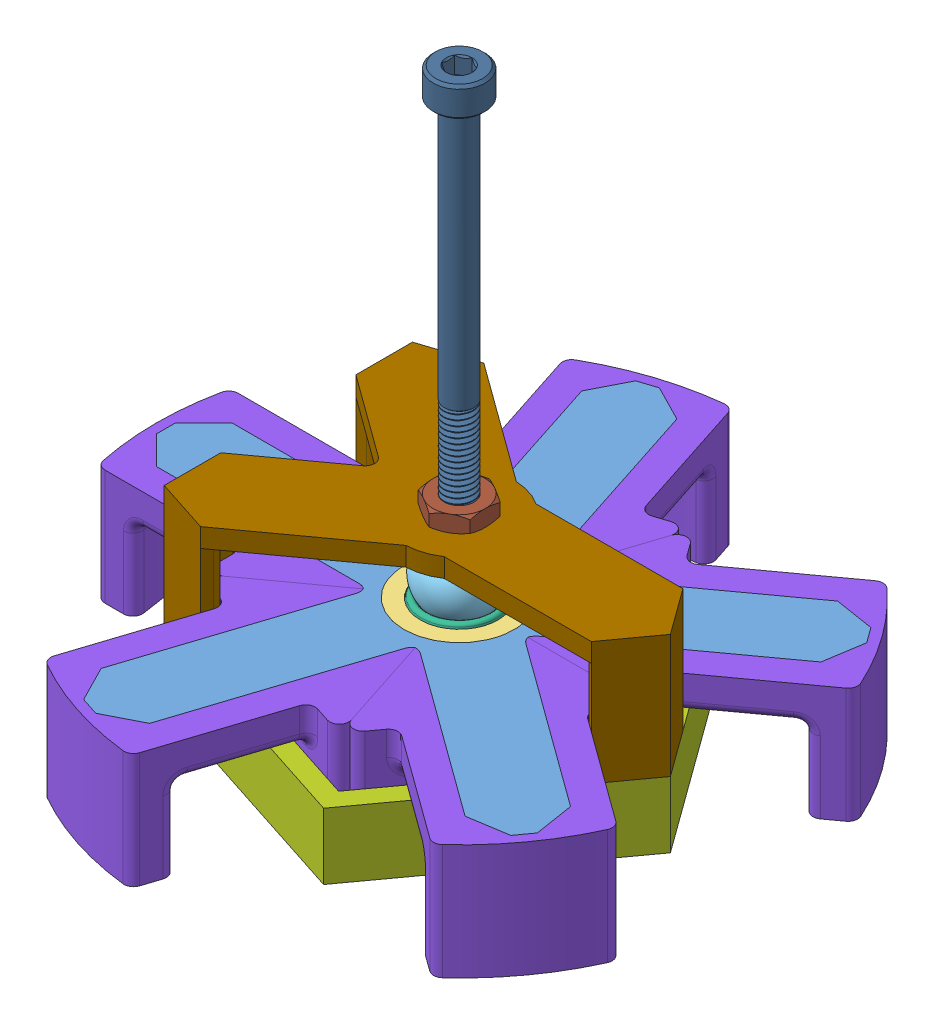
SolidWorks assembly Assem1, configuration Default. Lengths in mm.
Overall size (81.66 77.75 85.86).
15 component instances, 11 part files, 43 mates.
Components (placement in the parent):
- Fingerpad-1: Fingerpad [Default] x (-1 0 0) z (0 0 1) size (72.11 12.98 75.83)
- KJ_D63_N52 - 0.375 x 0.1875 Disk Magnet-1: KJ_D63_N52 - 0.375 x 0.1875 Disk Magnet [Default] at (0 -7.6895 0) x (0.401704 0 0.915769) z (0.915769 0 -0.401704) size (9.53 4.76 9.53)
- Magnet Holder-1: Magnet Holder [Default] x (0.401704 0 0.915769) z (0.915769 0 -0.401704) size (23.49 7.56 23.49)
- Magnet Retainer-1: Magnet Retainer [Default] at (0 -10.0708 0) x (0.401704 0 0.915769) z (0 -1 0) size (18.41 18.41 7.3)
- Threaded Magnetic Ball - M4-1: Threaded Magnetic Ball - M4 [Default] at (0 0.5386 0) x (-0.837169 0 -0.546944) z (-0.546944 0 0.837169) size (10 9.47 10)
- 90333A007 - Flanged Countersunk Washer - #6-1: 90333A007 - Flanged Countersunk Washer - #6 [90333A007] at (0 -4.7697 0) size (13.33 2.79 13.33)
- Mold Bottom-1: Mold Bottom [Default] at origin size (51.4 9.51 54.05)
- Mold Top-2: Mold Top [Default] x (-1 0 0) z (0 0 1) size (33.27 15.52 27.08)
- Mold Top-4: Mold Top [Default] x (-0.309017 0 0.951057) z (0.951057 0 0.309017) size (33.27 15.52 27.08)
- Mold Top-5: Mold Top [Default] x (0.809017 0 0.587785) z (0.587785 0 -0.809017) size (33.27 15.52 27.08)
- Mold Top-6: Mold Top [Default] x (0.809017 0 -0.587785) z (-0.587785 0 -0.809017) size (33.27 15.52 27.08)
- Mold Top-7: Mold Top [Default] x (-0.309017 0 -0.951057) z (-0.951057 0 0.309017) size (33.27 15.52 27.08)
- Mold Support-1: Mold Support [Default] at (0 -9.1439 0) x (1 0 0) z (0 1 0) size (51.4 38.11 16.57)
- 91292A268 - SHCS - M4x55mm-1: 91292A268 - SHCS - M4x55mm [91292A268] at (0 0.5386 0) x (1 0 0) z (0 -1 0) size (7 7 59.38)
- 90695A035 - Nut - M4-1: 90695A035 - Nut - M4 [90695A035] at (0 8.522 0) size (7 2.75 8.08)
Mates (geometry in assembly coordinates):
- Coincident2: coincident anti-aligned: plane of Fingerpad-1; plane of assembly through (0 0 0) normal (0 1 0)
- Coincident3: coincident aligned: plane of Fingerpad-1 through (0 0 0) normal (0 0 1); plane of assembly through (0 0 0) normal (0 0 1)
- Coincident4: coincident anti-aligned: plane of Fingerpad-1; plane of assembly through (0 0 0) normal (1 0 0)
- Concentric1: concentric anti-aligned: cylinder of KJ_D63_N52 - 0.375 x 0.1875 Disk Magnet-1 through (0 -10.0708 0) axis (0 1 0) radius 4.7625; cylinder of Magnet Retainer-1 through (0 13.5503 0) axis (0 -1 0) radius 4.8895
- Coincident5: coincident aligned: plane of KJ_D63_N52 - 0.375 x 0.1875 Disk Magnet-1 through (0 -5.3083 0) normal (0 1 0); plane of Magnet Retainer-1 through (1.9138 -5.3083 1.2503) normal (0 1 0)
- Concentric2: concentric aligned: cylinder of Magnet Holder-1 through (0 -10.4486 0) axis (0 -1 0) radius 6.7945; cylinder of Magnet Retainer-1 through (0 13.5503 0) axis (0 -1 0) radius 6.6675
- Coincident7: coincident aligned: cone of Magnet Holder-1 through (0 -4.5463 0) axis (0 1 0); cone of 90333A007 - Flanged Countersunk Washer - #6-1 through (0 -2.3315 0) axis (0 1 0)
- Parallel1: parallel aligned: plane of 90333A007 - Flanged Countersunk Washer - #6-1 through (0 -4.7697 0) normal (0 0 1); plane of assembly through (0 0 0) normal (0 0 1)
- Coincident9: coincident anti-aligned: plane of Magnet Holder-1 through (2.7294 -10.0708 6.2222) normal (0 -1 0); plane of Magnet Retainer-1 through (0 -10.0708 0) normal (0 1 0)
- Concentric3: concentric aligned: cylinder of Fingerpad-1 through (0 -13.8808 0) axis (0 -1 0) radius 11.7475; cylinder of Magnet Holder-1 through (0 -10.4486 0) axis (0 -1 0) radius 11.7475
- Coincident10: coincident anti-aligned: plane of Fingerpad-1 through (-11.7475 -10.0708 0) normal (0 1 0); plane of Magnet Holder-1 through (2.7294 -10.0708 6.2222) normal (0 -1 0)
- Concentric4: concentric anti-aligned: cylinder of Threaded Magnetic Ball - M4-1 through (0 5.5386 0) axis (0 1 0) radius 2.25; cylinder of 90333A007 - Flanged Countersunk Washer - #6-1 through (0 -4.7697 0) axis (0 -1 0) radius 2.286
- Tangent2: tangent aligned: sphere of Threaded Magnetic Ball - M4-1; cone of 90333A007 - Flanged Countersunk Washer - #6-1 through (0 -4.5157 0) axis (0 -1 0)
- InPlace1: in place: plane of ? through (0 0 0) normal (0 0 1); plane of ? through (0 0 0) normal (0 0 1); moOrthogonalPlaneRef_w of ? through (0 0 0) normal (0 0 1); line of ? through (-55 0 0) axis (0 0 -1); plane of ? through (0 0 0) normal (0 0 1); line of ? through (55 -55 0) axis (0 0 -1); plane of ? through (0 0 0) normal (0 0 1); unknown of ?
- Coincident11: coincident aligned: plane of Fingerpad-1; plane of ?
- Coincident12: coincident aligned: moOrthogonalPlaneRef_w of Fingerpad-1 through (-7.1388 0 0) axis (0 0 -1); plane of ?
- Coincident13: coincident anti-aligned: moOrthogonalPlaneRef_w of Fingerpad-1 through (7.1388 -7.1388 0) axis (0 0 1); plane of ?
- InPlace2: in place: plane of Mold Bottom-1 through (0 0 0) normal (0 0 1); plane of Mold Bottom-1 through (0 0 0) normal (0 1 0); plane of Mold Bottom-1 through (0 0 0) normal (1 0 0); unknown of Mold Bottom-1
- Coincident14: coincident aligned: plane of Mold Bottom-1; plane of assembly
- Coincident15: coincident aligned: plane of Mold Bottom-1 through (0 0 0) normal (0 1 0); moOrthogonalPlaneRef_w of assembly
- Coincident16: coincident anti-aligned: plane of Mold Bottom-1 through (0 0 0) normal (1 0 0); moOrthogonalPlaneRef_w of assembly
- InPlace3: in place: plane of ? through (-7.4295 -2.5143 0) normal (0 1 0); plane of ? through (0 -2.5143 0) normal (0 1 0); plane of ? through (-7.4295 -2.5143 0) normal (0 1 0); plane of ? through (0 -2.5143 0) normal (0 0 -1); plane of ? through (-7.4295 -2.5143 0) normal (0 1 0); line of ? through (-55 0 -2.5143) axis (0 1 0); plane of ? through (-7.4295 -2.5143 0) normal (0 1 0); unknown of ?
- Coincident17: coincident aligned: plane of Fingerpad-1; plane of ?
- Coincident18: coincident aligned: moOrthogonalPlaneRef_w of Fingerpad-1 through (0 -2.5143 0) normal (0 0 -1); plane of ? through (0 -2.5143 0) normal (0 0 -1)
- Coincident19: coincident anti-aligned: moOrthogonalPlaneRef_w of Fingerpad-1 through (0 -2.5143 0) normal (-1 0 0); plane of ?
- Coincident20: coincident anti-aligned: plane of Fingerpad-1 through (0 -4.5463 0) normal (0 -1 0); plane of Mold Top-5 through (0 -4.5463 0) normal (0 1 0)
- Coincident21: coincident anti-aligned: plane of Fingerpad-1 through (32.663 -4.5463 22.1612) normal (0.809017 0 0.587785); plane of Mold Top-5 through (32.663 -4.5463 22.1612) normal (-0.809017 0 -0.587785)
- Coincident22: coincident anti-aligned: plane of Fingerpad-1 through (9.2161 -4.5463 0.4167) normal (0.587785 0 -0.809017); plane of Mold Top-5 through (9.2161 -4.5463 0.4167) normal (-0.587785 0 0.809017)
- Coincident23: coincident anti-aligned: plane of Fingerpad-1 through (0 -4.5463 0) normal (0 -1 0); plane of Mold Top-2 through (0 -4.5463 0) normal (0 1 0)
- Coincident24: coincident anti-aligned: plane of Fingerpad-1 through (-39.4509 -4.5463 1.27) normal (-1 0 0); plane of Mold Top-2 through (-39.4509 -4.5463 1.27) normal (1 0 0)
- Coincident25: coincident anti-aligned: plane of Fingerpad-1 through (-7.7009 -4.5463 5.08) normal (0 0 1); plane of Mold Top-2 through (-7.7009 -4.5463 5.08) normal (0 0 -1)
- InPlace4: in place: plane of ? through (-1.27 -2.5143 0) normal (0 1 0); plane of ? through (0 -2.5143 0) normal (0 1 0); plane of ? through (-1.27 -2.5143 0) normal (0 1 0); plane of ? through (0 -2.5143 0) normal (0 0 -1); plane of ? through (-1.27 -2.5143 0) normal (0 1 0); unknown of ?; plane of ? through (-1.27 -2.5143 0) normal (0 1 0); unknown of ?
- Coincident26: coincident aligned: plane of Mold Top-2; plane of ?
- Coincident27: coincident aligned: moOrthogonalPlaneRef_w of Mold Top-2 through (0 -2.5143 0) normal (0 0 -1); plane of ? through (0 -2.5143 0) normal (0 0 -1)
- Coincident28: coincident anti-aligned: moOrthogonalPlaneRef_w of Mold Top-2 through (0 -2.5143 0) normal (-1 0 0); plane of ?
- InPlace5: in place: plane of Mold Bottom-1 through (0 -9.1439 0) normal (0 1 0); plane of Mold Support-1 through (0 -9.1439 0) normal (0 1 0); plane of Mold Bottom-1 through (0 -9.1439 0) normal (0 1 0); plane of Mold Support-1 through (0 -9.1439 0) normal (0 0 -1); plane of Mold Bottom-1 through (0 -9.1439 0) normal (0 1 0); line of Mold Support-1 through (-55 0 -9.1439) axis (0 1 0); plane of Mold Bottom-1 through (0 -9.1439 0) normal (0 1 0); unknown of Mold Support-1
- Coincident29: coincident aligned: plane of Mold Bottom-1; plane of Mold Support-1
- Coincident30: coincident aligned: moOrthogonalPlaneRef_w of Mold Bottom-1 through (0 -9.1439 0) normal (0 0 -1); plane of Mold Support-1 through (0 -9.1439 0) normal (0 0 -1)
- Coincident31: coincident anti-aligned: moOrthogonalPlaneRef_w of Mold Bottom-1 through (0 -9.1439 0) normal (-1 0 0); plane of Mold Support-1
- Concentric5: concentric anti-aligned: cylinder of Mold Support-1 through (0 7.422 0) axis (0 1 0) radius 2.25; cylinder of 91292A268 - SHCS - M4x55mm-1 through (0 59.5386 0) axis (0 -1 0) radius 3.5
- Coincident26: coincident: moEndPointRef_w of Threaded Magnetic Ball - M4-1; plane of 91292A268 - SHCS - M4x55mm-1 through (0 0.5386 0) normal (0 -1 0)
- Concentric6: concentric anti-aligned: cylinder of 91292A268 - SHCS - M4x55mm-1 through (0 55.5386 0) axis (0 -1 0) radius 2; circle of 90695A035 - Nut - M4-1
- Coincident27: coincident anti-aligned: plane of Mold Support-1 through (0 7.422 0) normal (0 1 0); plane of 90695A035 - Nut - M4-1 through (-3.5 7.422 -2.0207) normal (0 -1 0)
